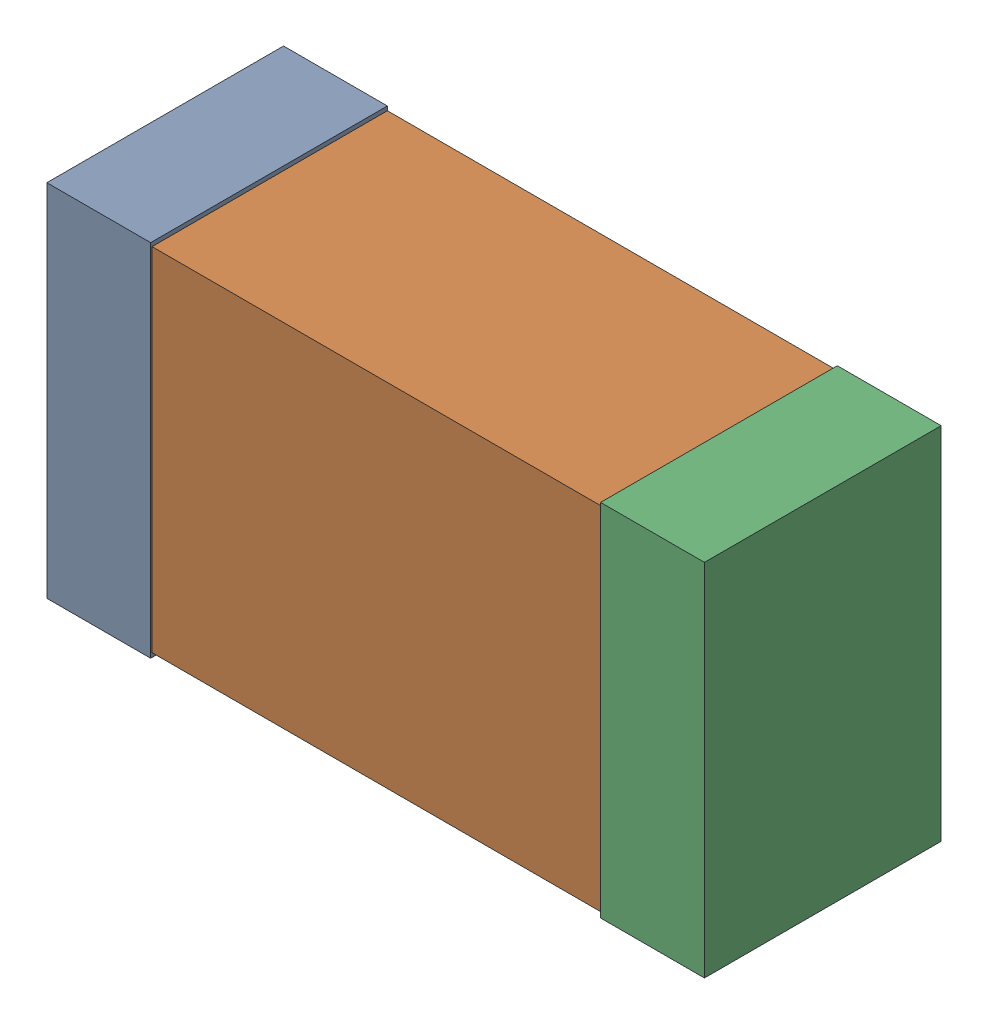
SolidWorks assembly USB45_C6, configuration Default. Lengths in mm.
Overall size (2.38 1.3 0.85).
6 component instances, 2 part files, 0 mates.
Components (placement in the parent):
- 384311232-1: 384311232 [Default] at (148.86 34.163 0) size (0.38 1.3 0.85)
  - Extruded_8-1: Extruded_8 [Default] at origin size (0.38 1.3 0.85)
- 384311360-1: 384311360 [Default] at (149.86 34.163 0) size (2.2 1.27 0.85)
  - Extruded_9-1: Extruded_9 [Default] at origin size (2.2 1.27 0.85)
- 384311232-2: 384311232 [Default] at (150.86 34.163 0) size (0.38 1.3 0.85)
  - Extruded_8-1: Extruded_8 [Default] at origin size (0.38 1.3 0.85)
